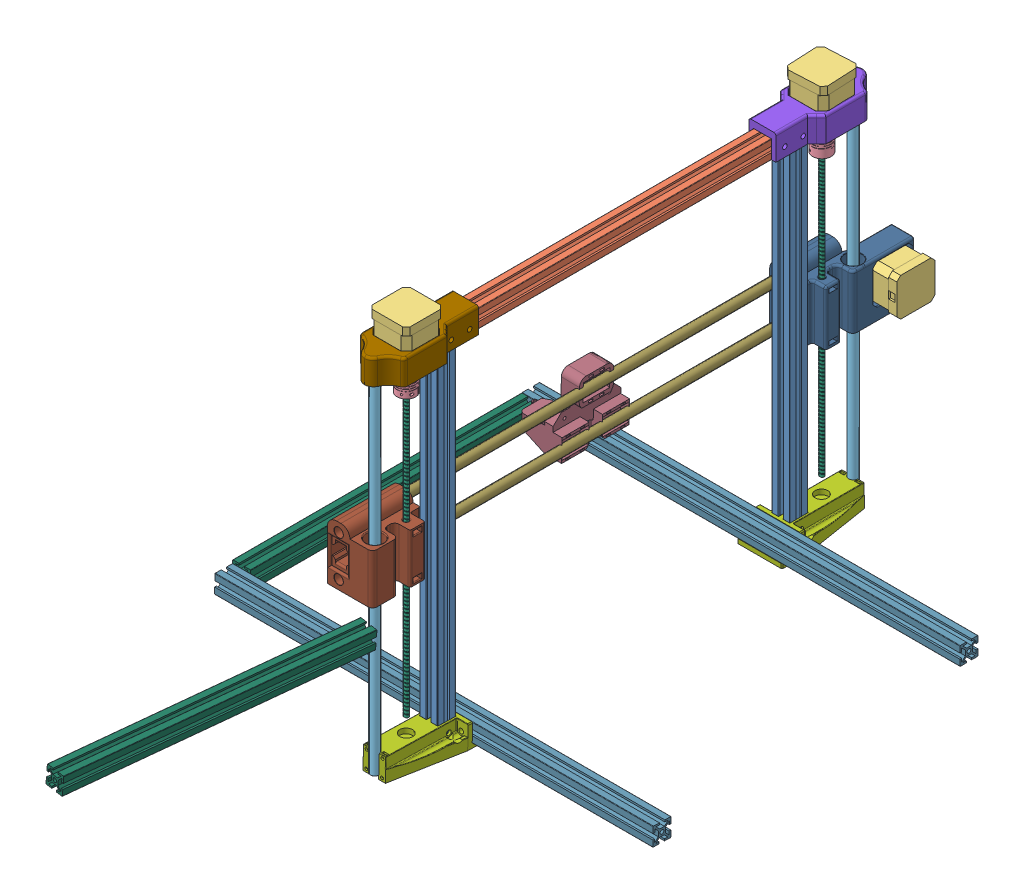
SolidWorks assembly sE1X Gantry Assembly, configuration Default. Lengths in mm.
Overall size (488.22 435.59 911.85).
25 component instances, 15 part files, 42 mates.
Components (placement in the parent):
- sE1X 398mm Z axis 2020 extrusion-1: sE1X 398mm Z axis 2020 extrusion [Default] at origin size (20 398 20)
- sE1X 398mm Z axis 2020 extrusion-3: sE1X 398mm Z axis 2020 extrusion [Default] at (0 0 390) size (20 398 20)
- 370mm X axis 2020 extrusion-4: 370mm X axis 2020 extrusion [Default] at (0 410 -40) x (-1 0 0) z (0 1 0) size (20 370 20)
- nema17-1: nema17 [Défaut] at (0.3968 404.3307 424.9) x (1 0 0) z (0 1 0) size (42 42 71)
- nema17-2: nema17 [Défaut] at (0.2968 404.8 -35.12) x (0.998806 0 -0.048861) z (0 1 0) size (42 42 71)
- 5mm coupler-1: 5mm coupler [Valor predeterminado] at (0.2968 383.0903 -35.12) x (0 -1 0) z (-0.000286 0 1) size (25 20.35 21.4)
- 5mm coupler-2: 5mm coupler [Valor predeterminado] at (0.3968 382.7752 424.9) x (0 1 0) z (0.001793 0 0.999998) size (25 20.35 21.4)
- sE1X 398mm 10mm smooth rod-1: sE1X 398mm 10mm smooth rod [Default] at (0.2968 22.246 459.8) x (-0.139408 0 0.990235) z (0 1 0) size (10 10 390)
- sE1X 398mm 10mm smooth rod-2: sE1X 398mm 10mm smooth rod [Default] at (0.2968 409.8 -69.8) x (0.998806 0 -0.048861) z (0 -1 0) size (10 10 390)
- 5mm threaded rod-1: 5mm threaded rod [Default] at (0.3968 59.2307 424.9) x (0.999998 0 -0.001793) z (0.001793 0 0.999998) size (5.07 324.29 5)
- 5mm threaded rod-2: 5mm threaded rod [Default] at (0.2968 59.7 -35.12) x (0.998806 0 -0.048861) z (0.048861 0 0.998806) size (5.07 324.29 5)
- sE1X Z Axis bottom bracket-1: sE1X Z Axis bottom bracket [Default] at (0.1 28.7042 356.4908) x (1 0 0) z (0 0.022807 0.99974) size (50 25 103.66)
- sE1X Z Axis bottom bracket-2: sE1X Z Axis bottom bracket [Default] at (-0.1 29.25 33.6) x (-1 0 0) z (0 0 -1) size (50 25 103.66)
- sE1X Z Axis top motor bracket(mirrored)-1: sE1X Z Axis top motor bracket(mirrored) [Mirrored] at (-0.2968 399.8 95.2) size (50 27.84 222.86)
- sE1X Z Axis top motor bracket-3: sE1X Z Axis top motor bracket [Default] at (0.2968 399.8 424.8) size (50 27.84 111.43)
- sE1X X Axis Motor end-1: sE1X X Axis Motor end [Default] at (-12.2032 225.0682 -69.8) x (0 0 -1) z (1 0 0) size (110 70.43 50)
- sE1X X idler end-1: sE1X X idler end [Default] at (-37.2032 225.0682 439.8) x (0 0 -1) z (1 0 0) size (70 65 50)
- sE1X 465mm 10mm smooth rod-3: sE1X 465mm 10mm smooth rod [Default] at (-24.7032 202.5682 -41.1928) size (10 10 465)
- sE1X 465mm 10mm smooth rod-4: sE1X 465mm 10mm smooth rod [Default] at (-24.7032 247.5682 -41.9198) size (10 10 465)
- SE1X 10mm carriage(BOWDEN)-1: SE1X 10mm carriage(BOWDEN) [10mm config] at (-34.1719 229.9676 189.1374) x (0 0 1) z (-0.019456 -0.999811 0) size (75 52.26 71.73)
- nema17-3: nema17 [Défaut] at (-8.7032 225.0682 -101.05) x (0 0 -1) z (1 0 0) size (42 42 71)
- sE1X 485mm Z axis 2020 extrusion-1: sE1X 485mm Z axis 2020 extrusion [Default] at (159.913 31.3339 366.5335) x (0 0.99974 -0.022807) z (0 0.022807 0.99974) size (20 485 20)
- sE1X 485mm Z axis 2020 extrusion-2: sE1X 485mm Z axis 2020 extrusion [Default] at (156.6901 31.65 23.5) x (0 1 0) z (0 0 1) size (20 485 20)
- 320mm X axis 2020 extrusion-1: 320mm X axis 2020 extrusion [Default] at (-253.3099 31.65 -66.5) x (-1 0 0) z (0 1 0) size (20 320 20)
- 320mm X axis 2020 extrusion-2: 320mm X axis 2020 extrusion [Default] at (-36.2502 166.0503 885.6768) x (-0.993686 0.069383 -0.088171) z (-0.070502 -0.997465 0.00963) size (20 320 20)
Mates (geometry in assembly coordinates):
- Concentric5: concentric anti-aligned: cylinder of nema17-2 through (0.2968 380.8 -35.12) axis (0 1 0) radius 2.5; cylinder of 5mm coupler-1 through (0.2968 370.5903 -35.12) axis (0 -1 0) radius 2.5
- Concentric7: concentric aligned: cylinder of nema17-1 through (0.3968 380.3307 424.9) axis (0 1 0) radius 2.5; cylinder of 5mm coupler-2 through (0.3968 395.2752 424.9) axis (0 1 0) radius 2.5
- Coincident38: coincident anti-aligned: plane of nema17-2 through (0.2968 380.8 -35.12) normal (0 -1 0); plane of 5mm threaded rod-2 through (0.2968 380.8 -35.12) normal (0 1 0)
- Concentric16: concentric aligned: cylinder of 5mm coupler-1 through (0.2968 370.5903 -35.12) axis (0 -1 0) radius 2.5; cylinder of 5mm threaded rod-2 through (0.2968 380.8 -35.12) axis (0 -1 0) radius 2.5
- Coincident39: coincident anti-aligned: plane of nema17-1 through (0.3968 380.3307 424.9) normal (0 -1 0); plane of 5mm threaded rod-1 through (0.3968 380.3307 424.9) normal (0 1 0)
- Concentric17: concentric anti-aligned: cylinder of 5mm coupler-2 through (0.3968 395.2752 424.9) axis (0 1 0) radius 2.5; cylinder of 5mm threaded rod-1 through (0.3968 380.3307 424.9) axis (0 -1 0) radius 2.5
- Coincident57: coincident: point of sE1X 398mm Z axis 2020 extrusion-3; point of sE1X Z Axis bottom bracket-1
- Coincident60: coincident anti-aligned: plane of sE1X 398mm Z axis 2020 extrusion-3 through (-10 22 380.5) normal (-1 0 0); plane of sE1X Z Axis bottom bracket-1 through (-10 21.7444 380.2558) normal (1 0 0)
- Coincident64: coincident aligned: plane of sE1X 398mm Z axis 2020 extrusion-1 through (10 22 9.5) normal (1 0 0); plane of 370mm X axis 2020 extrusion-4 through (10 400.5 10) normal (1 0 0)
- Coincident65: coincident aligned: plane of sE1X 398mm Z axis 2020 extrusion-1 through (9.5 420 -9.5) normal (0 1 0); plane of 370mm X axis 2020 extrusion-4 through (9.5 420 10) normal (0 1 0)
- Coincident71: coincident anti-aligned: plane of sE1X 398mm Z axis 2020 extrusion-3 through (-3 22 380) normal (0 0 -1); plane of 370mm X axis 2020 extrusion-4 through (-9.5 400.5 380) normal (0 0 1)
- Coincident72: coincident anti-aligned: plane of sE1X 398mm Z axis 2020 extrusion-1 through (-9.5 22 10) normal (0 0 1); plane of 370mm X axis 2020 extrusion-4 through (-9.5 400.5 10) normal (0 0 -1)
- Tangent4: tangent anti-aligned: plane of sE1X 398mm Z axis 2020 extrusion-3 through (3 22 400) normal (0 0 1); cylinder of sE1X Z Axis bottom bracket-1 through (10.2 41.9556 400.25) axis (1 0 0) radius 0.25
- Coincident76: coincident anti-aligned: line of sE1X 398mm Z axis 2020 extrusion-1 through (3 22 10) axis (1 0 0); line of sE1X Z Axis bottom bracket-2 through (9.75 22 10) axis (-1 0 0)
- Coincident77: coincident anti-aligned: plane of sE1X 398mm Z axis 2020 extrusion-1 through (10 22 9.5) normal (1 0 0); plane of sE1X Z Axis bottom bracket-2 through (10 21.75 10) normal (-1 0 0)
- Coincident89: coincident anti-aligned: line of sE1X 398mm Z axis 2020 extrusion-3 through (3 420 400) axis (1 0 0); line of sE1X Z Axis top motor bracket-3 through (10.5936 420 400) axis (-1 0 0)
- Coincident90: coincident anti-aligned: line of sE1X 398mm Z axis 2020 extrusion-3 through (-10 420 393) axis (0 0 1); line of sE1X Z Axis top motor bracket-3 through (-10 420 400) axis (0 0 -1)
- Concentric18: concentric aligned: cylinder of sE1X 398mm 10mm smooth rod-2 through (0.2968 19.8 -69.8) axis (0 1 0) radius 5; cylinder of sE1X X Axis Motor end-1 through (0.2968 175.0682 -69.8) axis (0 1 0) radius 9.55
- Lock3: lock: unknown of sE1X 398mm 10mm smooth rod-2; unknown of sE1X Z Axis top motor bracket(mirrored)-1
- Lock4: lock: unknown of 370mm X axis 2020 extrusion-4; unknown of sE1X Z Axis top motor bracket(mirrored)-1
- Lock5: lock: unknown of 370mm X axis 2020 extrusion-4; unknown of sE1X Z Axis top motor bracket-3
- Parallel2: parallel aligned: cylinder of sE1X 398mm 10mm smooth rod-2 through (0.2968 19.8 -69.8) axis (0 1 0) radius 5; cylinder of sE1X Z Axis bottom bracket-2 through (-0.1 16.7499 -70) axis (0 1 0) radius 5.05
- Coincident94: coincident anti-aligned: plane of nema17-1 through (-14.4032 442.3307 445.9) normal (0 0 1); plane of sE1X Z Axis top motor bracket-3 through (-20.8032 404.8 445.9) normal (0 0 -1)
- Coincident96: coincident anti-aligned: plane of nema17-1 through (21.3968 442.3307 410.1) normal (1 0 0); plane of sE1X Z Axis top motor bracket-3 through (21.3968 404.8 445.9) normal (-1 0 0)
- Concentric27: concentric aligned: cylinder of sE1X 398mm 10mm smooth rod-1 through (0.2968 412.246 459.8) axis (0 -1 0) radius 5; cylinder of sE1X Z Axis top motor bracket-3 through (0.2968 409.8 459.8) axis (0 -1 0) radius 5.05
- Concentric32: concentric anti-aligned: cylinder of sE1X 398mm 10mm smooth rod-1 through (0.2968 412.246 459.8) axis (0 -1 0) radius 5; cylinder of sE1X X idler end-1 through (0.2968 192.5682 459.8) axis (0 1 0) radius 9.55
- Concentric33: concentric anti-aligned: cylinder of sE1X X Axis Motor end-1 through (-24.7032 202.5682 -44.8) axis (0 0 1) radius 5.05; cylinder of sE1X 465mm 10mm smooth rod-3 through (-24.7032 202.5682 423.8072) axis (0 0 -1) radius 5
- Concentric34: concentric anti-aligned: cylinder of sE1X X Axis Motor end-1 through (-24.7032 247.5682 -44.8) axis (0 0 1) radius 5.05; cylinder of sE1X 465mm 10mm smooth rod-4 through (-24.7032 247.5682 423.0802) axis (0 0 -1) radius 5
- Concentric35: concentric aligned: cylinder of sE1X X idler end-1 through (-24.7032 247.5682 474.8) axis (0 0 -1) radius 5.05; cylinder of sE1X 465mm 10mm smooth rod-4 through (-24.7032 247.5682 423.0802) axis (0 0 -1) radius 5
- Concentric36: concentric anti-aligned: circle of sE1X X idler end-1; cylinder of sE1X 465mm 10mm smooth rod-3 through (-24.7032 202.5682 423.8072) axis (0 0 -1) radius 5
- Concentric40: concentric aligned: cylinder of sE1X 465mm 10mm smooth rod-3 through (-24.7032 202.5682 423.8072) axis (0 0 -1) radius 5; circle of SE1X 10mm carriage(BOWDEN)-1
- Coincident97: coincident anti-aligned: plane of sE1X X Axis Motor end-1 through (-8.7032 225.0682 -69.8) normal (1 0 0); plane of nema17-3 through (-8.7032 225.0682 -101.05) normal (-1 0 0)
- Concentric41: concentric aligned: circle of sE1X X Axis Motor end-1; circle of nema17-3
- Parallel7: parallel anti-aligned: plane of sE1X X Axis Motor end-1 through (-8.7032 203.8182 -79.8) normal (0 0 -1); plane of nema17-3 through (29.2968 239.8682 -80.05) normal (0 0 1)
- Coincident102: coincident anti-aligned: plane of sE1X Z Axis bottom bracket-1 through (-24.9 41.6593 376.3005) normal (0 -0.022807 -0.99974); plane of sE1X 485mm Z axis 2020 extrusion-1 through (224.913 34.5612 376.4625) normal (0 0.022807 0.99974)
- Coincident103: coincident anti-aligned: plane of sE1X Z Axis bottom bracket-1 through (-24.9 21.1061 356.6642) normal (0 0.99974 -0.022807); plane of sE1X 485mm Z axis 2020 extrusion-1 through (224.913 21.4049 369.7608) normal (0 -0.99974 0.022807)
- Coincident106: coincident anti-aligned: plane of sE1X Z Axis bottom bracket-2 through (24.9 41.75 13.5) normal (0 0 1); plane of sE1X 485mm Z axis 2020 extrusion-2 through (221.6901 41.15 13.5) normal (0 0 -1)
- Coincident107: coincident anti-aligned: plane of sE1X Z Axis bottom bracket-2 through (24.9 21.65 33.6) normal (0 1 0); plane of sE1X 485mm Z axis 2020 extrusion-2 through (221.6901 21.65 14) normal (0 -1 0)
- Coincident111: coincident anti-aligned: plane of sE1X 485mm Z axis 2020 extrusion-2 through (221.6901 34.65 33.5) normal (0 0 1); plane of 320mm X axis 2020 extrusion-1 through (-262.8099 22.15 33.5) normal (0 0 -1)
- Parallel8: parallel aligned: cylinder of sE1X 485mm Z axis 2020 extrusion-2 through (221.6901 41.15 33) axis (-1 0 0) radius 0.5; line of 320mm X axis 2020 extrusion-1 through (-243.8099 41.65 33.5) axis (-1 0 0)
- Parallel10: parallel anti-aligned: cylinder of sE1X 485mm Z axis 2020 extrusion-2 through (221.6901 22.15 33) axis (-1 0 0) radius 0.5; line of 320mm X axis 2020 extrusion-1 through (-262.8099 21.65 33.5) axis (1 0 0)
- Coincident123: coincident: point of sE1X 485mm Z axis 2020 extrusion-2; point of 320mm X axis 2020 extrusion-1
